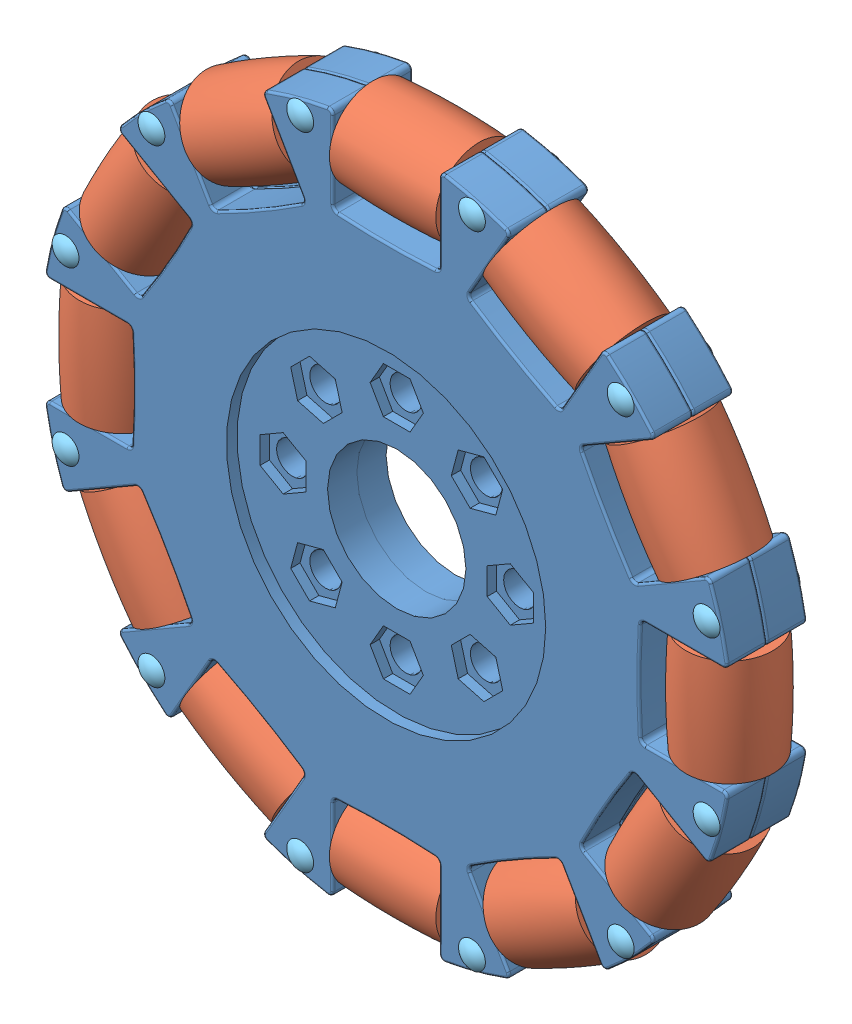
SolidWorks assembly omni assembly, configuration Default. Lengths in mm.
Overall size (136.3 136.3 22.3).
98 component instances, 5 part files, 11 mates.
Components (placement in the parent):
- omni 1-1: omni 1 [Default] at (56.9686 68.7963 88.8903) size (128.13 128.13 7.52)
- omni 1-2: omni 1 [Default] at (56.9686 68.7963 88.8903) x (-1 0 0) z (0 0 -1) size (128.13 128.13 7.52)
- roller assembly-1: roller assembly [Default] at (50.0152 30.7738 88.0959) x (1 0 0) z (0 -0.918252 -0.395997) size (24 16.97 16.97)
  - omni3-1: omni3 [Default] at (-3.0466 8.2445 17.1115) size (20 16.97 16.97)
  - omni4-1: omni4 [Default] at (-5.0466 8.2445 17.1115) x (0 0.996795 -0.079995) z (1 0 0) size (3 3 24)
  - instrument ball bearing_68_am-1: instrument ball bearing_68_am [AFBMA 12.1.4.1 - 0030-8 - 8,DE,NC,8_68] at (15.4534 8.2445 17.1115) size (3 8 8)
  - instrument ball bearing_68_am-2: instrument ball bearing_68_am [AFBMA 12.1.4.1 - 0030-8 - 8,DE,NC,8_68] at (-1.5466 8.2445 17.1115) size (3 8 8)
- truss head rivets gb-1: truss head rivets gb [GB_RIVETS_ROUND_TYPE87 2X11] at (101.0484 112.8761 80.3612) x (0 0 1) z (-1 0 0) size (12.03 5.04 5.04)
- truss head rivets gb-2: truss head rivets gb [GB_RIVETS_ROUND_TYPE87 2X11] at (101.0484 112.8761 93.4194) x (0 0 -1) z (1 0 0) size (12.03 5.04 5.04)
- truss head rivets gb-3: truss head rivets gb [GB_RIVETS_ROUND_TYPE87 2X11] at (101.0484 112.8761 97.4194) x (0 0 -1) z (1 0 0) size (12.03 5.04 5.04)
- roller assembly-2: roller assembly [Default] at (31.9355 39.3446 88.0959) x (0.866025 -0.5 0) z (-0.459126 -0.795229 -0.395997) size (24 16.97 16.97)
  - omni3-1: omni3 [Default] at (-3.0466 8.2445 17.1115) size (20 16.97 16.97)
  - omni4-1: omni4 [Default] at (-5.0466 8.2445 17.1115) x (0 0.996795 -0.079995) z (1 0 0) size (3 3 24)
  - instrument ball bearing_68_am-1: instrument ball bearing_68_am [AFBMA 12.1.4.1 - 0030-8 - 8,DE,NC,8_68] at (15.4534 8.2445 17.1115) size (3 8 8)
  - instrument ball bearing_68_am-2: instrument ball bearing_68_am [AFBMA 12.1.4.1 - 0030-8 - 8,DE,NC,8_68] at (-1.5466 8.2445 17.1115) size (3 8 8)
- roller assembly-3: roller assembly [Default] at (20.5635 55.8069 88.0959) x (0.5 -0.866025 0) z (-0.795229 -0.459126 -0.395997) size (24 16.97 16.97)
  - omni3-1: omni3 [Default] at (-3.0466 8.2445 17.1115) size (20 16.97 16.97)
  - omni4-1: omni4 [Default] at (-5.0466 8.2445 17.1115) x (0 0.996795 -0.079995) z (1 0 0) size (3 3 24)
  - instrument ball bearing_68_am-1: instrument ball bearing_68_am [AFBMA 12.1.4.1 - 0030-8 - 8,DE,NC,8_68] at (15.4534 8.2445 17.1115) size (3 8 8)
  - instrument ball bearing_68_am-2: instrument ball bearing_68_am [AFBMA 12.1.4.1 - 0030-8 - 8,DE,NC,8_68] at (-1.5466 8.2445 17.1115) size (3 8 8)
- roller assembly-4: roller assembly [Default] at (18.9461 75.7497 88.0959) x (0 -1 0) z (-0.918252 0 -0.395997) size (24 16.97 16.97)
  - omni3-1: omni3 [Default] at (-3.0466 8.2445 17.1115) size (20 16.97 16.97)
  - omni4-1: omni4 [Default] at (-5.0466 8.2445 17.1115) x (0 0.996795 -0.079995) z (1 0 0) size (3 3 24)
  - instrument ball bearing_68_am-1: instrument ball bearing_68_am [AFBMA 12.1.4.1 - 0030-8 - 8,DE,NC,8_68] at (15.4534 8.2445 17.1115) size (3 8 8)
  - instrument ball bearing_68_am-2: instrument ball bearing_68_am [AFBMA 12.1.4.1 - 0030-8 - 8,DE,NC,8_68] at (-1.5466 8.2445 17.1115) size (3 8 8)
- roller assembly-5: roller assembly [Default] at (27.5169 93.8294 88.0959) x (-0.5 -0.866025 0) z (-0.795229 0.459126 -0.395997) size (24 16.97 16.97)
  - omni3-1: omni3 [Default] at (-3.0466 8.2445 17.1115) size (20 16.97 16.97)
  - omni4-1: omni4 [Default] at (-5.0466 8.2445 17.1115) x (0 0.996795 -0.079995) z (1 0 0) size (3 3 24)
  - instrument ball bearing_68_am-1: instrument ball bearing_68_am [AFBMA 12.1.4.1 - 0030-8 - 8,DE,NC,8_68] at (15.4534 8.2445 17.1115) size (3 8 8)
  - instrument ball bearing_68_am-2: instrument ball bearing_68_am [AFBMA 12.1.4.1 - 0030-8 - 8,DE,NC,8_68] at (-1.5466 8.2445 17.1115) size (3 8 8)
- roller assembly-6: roller assembly [Default] at (43.9792 105.2015 88.0959) x (-0.866025 -0.5 0) z (-0.459126 0.795229 -0.395997) size (24 16.97 16.97)
  - omni3-1: omni3 [Default] at (-3.0466 8.2445 17.1115) size (20 16.97 16.97)
  - omni4-1: omni4 [Default] at (-5.0466 8.2445 17.1115) x (0 0.996795 -0.079995) z (1 0 0) size (3 3 24)
  - instrument ball bearing_68_am-1: instrument ball bearing_68_am [AFBMA 12.1.4.1 - 0030-8 - 8,DE,NC,8_68] at (15.4534 8.2445 17.1115) size (3 8 8)
  - instrument ball bearing_68_am-2: instrument ball bearing_68_am [AFBMA 12.1.4.1 - 0030-8 - 8,DE,NC,8_68] at (-1.5466 8.2445 17.1115) size (3 8 8)
- roller assembly-7: roller assembly [Default] at (63.922 106.8188 88.0959) x (-1 0 0) z (0 0.918252 -0.395997) size (24 16.97 16.97)
  - omni3-1: omni3 [Default] at (-3.0466 8.2445 17.1115) size (20 16.97 16.97)
  - omni4-1: omni4 [Default] at (-5.0466 8.2445 17.1115) x (0 0.996795 -0.079995) z (1 0 0) size (3 3 24)
  - instrument ball bearing_68_am-1: instrument ball bearing_68_am [AFBMA 12.1.4.1 - 0030-8 - 8,DE,NC,8_68] at (15.4534 8.2445 17.1115) size (3 8 8)
  - instrument ball bearing_68_am-2: instrument ball bearing_68_am [AFBMA 12.1.4.1 - 0030-8 - 8,DE,NC,8_68] at (-1.5466 8.2445 17.1115) size (3 8 8)
- roller assembly-8: roller assembly [Default] at (82.0017 98.2481 88.0959) x (-0.866025 0.5 0) z (0.459126 0.795229 -0.395997) size (24 16.97 16.97)
  - omni3-1: omni3 [Default] at (-3.0466 8.2445 17.1115) size (20 16.97 16.97)
  - omni4-1: omni4 [Default] at (-5.0466 8.2445 17.1115) x (0 0.996795 -0.079995) z (1 0 0) size (3 3 24)
  - instrument ball bearing_68_am-1: instrument ball bearing_68_am [AFBMA 12.1.4.1 - 0030-8 - 8,DE,NC,8_68] at (15.4534 8.2445 17.1115) size (3 8 8)
  - instrument ball bearing_68_am-2: instrument ball bearing_68_am [AFBMA 12.1.4.1 - 0030-8 - 8,DE,NC,8_68] at (-1.5466 8.2445 17.1115) size (3 8 8)
- roller assembly-9: roller assembly [Default] at (93.3738 81.7858 88.0959) x (-0.5 0.866025 0) z (0.795229 0.459126 -0.395997) size (24 16.97 16.97)
  - omni3-1: omni3 [Default] at (-3.0466 8.2445 17.1115) size (20 16.97 16.97)
  - omni4-1: omni4 [Default] at (-5.0466 8.2445 17.1115) x (0 0.996795 -0.079995) z (1 0 0) size (3 3 24)
  - instrument ball bearing_68_am-1: instrument ball bearing_68_am [AFBMA 12.1.4.1 - 0030-8 - 8,DE,NC,8_68] at (15.4534 8.2445 17.1115) size (3 8 8)
  - instrument ball bearing_68_am-2: instrument ball bearing_68_am [AFBMA 12.1.4.1 - 0030-8 - 8,DE,NC,8_68] at (-1.5466 8.2445 17.1115) size (3 8 8)
- roller assembly-10: roller assembly [Default] at (94.9911 61.8429 88.0959) x (0 1 0) z (0.918252 0 -0.395997) size (24 16.97 16.97)
  - omni3-1: omni3 [Default] at (-3.0466 8.2445 17.1115) size (20 16.97 16.97)
  - omni4-1: omni4 [Default] at (-5.0466 8.2445 17.1115) x (0 0.996795 -0.079995) z (1 0 0) size (3 3 24)
  - instrument ball bearing_68_am-1: instrument ball bearing_68_am [AFBMA 12.1.4.1 - 0030-8 - 8,DE,NC,8_68] at (15.4534 8.2445 17.1115) size (3 8 8)
  - instrument ball bearing_68_am-2: instrument ball bearing_68_am [AFBMA 12.1.4.1 - 0030-8 - 8,DE,NC,8_68] at (-1.5466 8.2445 17.1115) size (3 8 8)
- roller assembly-11: roller assembly [Default] at (86.4204 43.7633 88.0959) x (0.5 0.866025 0) z (0.795229 -0.459126 -0.395997) size (24 16.97 16.97)
  - omni3-1: omni3 [Default] at (-3.0466 8.2445 17.1115) size (20 16.97 16.97)
  - omni4-1: omni4 [Default] at (-5.0466 8.2445 17.1115) x (0 0.996795 -0.079995) z (1 0 0) size (3 3 24)
  - instrument ball bearing_68_am-1: instrument ball bearing_68_am [AFBMA 12.1.4.1 - 0030-8 - 8,DE,NC,8_68] at (15.4534 8.2445 17.1115) size (3 8 8)
  - instrument ball bearing_68_am-2: instrument ball bearing_68_am [AFBMA 12.1.4.1 - 0030-8 - 8,DE,NC,8_68] at (-1.5466 8.2445 17.1115) size (3 8 8)
- roller assembly-12: roller assembly [Default] at (69.9581 32.3912 88.0959) x (0.866025 0.5 0) z (0.459126 -0.795229 -0.395997) size (24 16.97 16.97)
  - omni3-1: omni3 [Default] at (-3.0466 8.2445 17.1115) size (20 16.97 16.97)
  - omni4-1: omni4 [Default] at (-5.0466 8.2445 17.1115) x (0 0.996795 -0.079995) z (1 0 0) size (3 3 24)
  - instrument ball bearing_68_am-1: instrument ball bearing_68_am [AFBMA 12.1.4.1 - 0030-8 - 8,DE,NC,8_68] at (15.4534 8.2445 17.1115) size (3 8 8)
  - instrument ball bearing_68_am-2: instrument ball bearing_68_am [AFBMA 12.1.4.1 - 0030-8 - 8,DE,NC,8_68] at (-1.5466 8.2445 17.1115) size (3 8 8)
- truss head rivets gb-4: truss head rivets gb [GB_RIVETS_ROUND_TYPE87 2X11] at (117.1827 84.9306 93.4194) x (0 0 -1) z (0.866025 -0.5 0) size (12.03 5.04 5.04)
- truss head rivets gb-5: truss head rivets gb [GB_RIVETS_ROUND_TYPE87 2X11] at (117.1827 52.662 93.4194) x (0 0 -1) z (0.5 -0.866025 0) size (12.03 5.04 5.04)
- truss head rivets gb-6: truss head rivets gb [GB_RIVETS_ROUND_TYPE87 2X11] at (101.0484 24.7166 93.4194) x (0 0 -1) z (0 -1 0) size (12.03 5.04 5.04)
- truss head rivets gb-7: truss head rivets gb [GB_RIVETS_ROUND_TYPE87 2X11] at (73.1029 8.5823 93.4194) x (0 0 -1) z (-0.5 -0.866025 0) size (12.03 5.04 5.04)
- truss head rivets gb-8: truss head rivets gb [GB_RIVETS_ROUND_TYPE87 2X11] at (40.8343 8.5823 93.4194) x (0 0 -1) z (-0.866025 -0.5 0) size (12.03 5.04 5.04)
- truss head rivets gb-9: truss head rivets gb [GB_RIVETS_ROUND_TYPE87 2X11] at (12.8889 24.7166 93.4194) x (0 0 -1) z (-1 0 0) size (12.03 5.04 5.04)
- truss head rivets gb-10: truss head rivets gb [GB_RIVETS_ROUND_TYPE87 2X11] at (-3.2455 52.662 93.4194) x (0 0 -1) z (-0.866025 0.5 0) size (12.03 5.04 5.04)
- truss head rivets gb-11: truss head rivets gb [GB_RIVETS_ROUND_TYPE87 2X11] at (-3.2455 84.9306 93.4194) x (0 0 -1) z (-0.5 0.866025 0) size (12.03 5.04 5.04)
- truss head rivets gb-12: truss head rivets gb [GB_RIVETS_ROUND_TYPE87 2X11] at (12.8889 112.8761 93.4194) x (0 0 -1) z (0 1 0) size (12.03 5.04 5.04)
- truss head rivets gb-13: truss head rivets gb [GB_RIVETS_ROUND_TYPE87 2X11] at (40.8343 129.0104 93.4194) x (0 0 -1) z (0.5 0.866025 0) size (12.03 5.04 5.04)
- truss head rivets gb-14: truss head rivets gb [GB_RIVETS_ROUND_TYPE87 2X11] at (73.1029 129.0104 93.4194) x (0 0 -1) z (0.866025 0.5 0) size (12.03 5.04 5.04)
- truss head rivets gb-15: truss head rivets gb [GB_RIVETS_ROUND_TYPE87 2X11] at (117.1827 84.9306 80.3612) x (0 0 1) z (-0.866025 0.5 0) size (12.03 5.04 5.04)
- truss head rivets gb-16: truss head rivets gb [GB_RIVETS_ROUND_TYPE87 2X11] at (117.1827 52.662 80.3612) x (0 0 1) z (-0.5 0.866025 0) size (12.03 5.04 5.04)
- truss head rivets gb-17: truss head rivets gb [GB_RIVETS_ROUND_TYPE87 2X11] at (101.0484 24.7166 80.3612) x (0 0 1) z (0 1 0) size (12.03 5.04 5.04)
- truss head rivets gb-18: truss head rivets gb [GB_RIVETS_ROUND_TYPE87 2X11] at (73.1029 8.5823 80.3612) x (0 0 1) z (0.5 0.866025 0) size (12.03 5.04 5.04)
- truss head rivets gb-19: truss head rivets gb [GB_RIVETS_ROUND_TYPE87 2X11] at (40.8343 8.5823 80.3612) x (0 0 1) z (0.866025 0.5 0) size (12.03 5.04 5.04)
- truss head rivets gb-20: truss head rivets gb [GB_RIVETS_ROUND_TYPE87 2X11] at (12.8889 24.7166 80.3612) x (0 0 1) z (1 0 0) size (12.03 5.04 5.04)
- truss head rivets gb-21: truss head rivets gb [GB_RIVETS_ROUND_TYPE87 2X11] at (-3.2455 52.662 80.3612) x (0 0 1) z (0.866025 -0.5 0) size (12.03 5.04 5.04)
- truss head rivets gb-22: truss head rivets gb [GB_RIVETS_ROUND_TYPE87 2X11] at (-3.2455 84.9306 80.3612) x (0 0 1) z (0.5 -0.866025 0) size (12.03 5.04 5.04)
- truss head rivets gb-23: truss head rivets gb [GB_RIVETS_ROUND_TYPE87 2X11] at (12.8889 112.8761 80.3612) x (0 0 1) z (0 -1 0) size (12.03 5.04 5.04)
- truss head rivets gb-24: truss head rivets gb [GB_RIVETS_ROUND_TYPE87 2X11] at (40.8343 129.0104 80.3612) x (0 0 1) z (-0.5 -0.866025 0) size (12.03 5.04 5.04)
- truss head rivets gb-25: truss head rivets gb [GB_RIVETS_ROUND_TYPE87 2X11] at (73.1029 129.0104 80.3612) x (0 0 1) z (-0.866025 -0.5 0) size (12.03 5.04 5.04)
- truss head rivets gb-26: truss head rivets gb [GB_RIVETS_ROUND_TYPE87 2X11] at (73.1029 129.0104 97.4194) x (0 0 -1) z (0.866025 0.5 0) size (12.03 5.04 5.04)
- truss head rivets gb-27: truss head rivets gb [GB_RIVETS_ROUND_TYPE87 2X11] at (40.8343 129.0104 97.4194) x (0 0 -1) z (0.5 0.866025 0) size (12.03 5.04 5.04)
- truss head rivets gb-28: truss head rivets gb [GB_RIVETS_ROUND_TYPE87 2X11] at (12.8889 112.8761 97.4194) x (0 0 -1) z (0 1 0) size (12.03 5.04 5.04)
- truss head rivets gb-29: truss head rivets gb [GB_RIVETS_ROUND_TYPE87 2X11] at (-3.2455 84.9306 97.4194) x (0 0 -1) z (-0.5 0.866025 0) size (12.03 5.04 5.04)
- truss head rivets gb-30: truss head rivets gb [GB_RIVETS_ROUND_TYPE87 2X11] at (-3.2455 52.662 97.4194) x (0 0 -1) z (-0.866025 0.5 0) size (12.03 5.04 5.04)
- truss head rivets gb-31: truss head rivets gb [GB_RIVETS_ROUND_TYPE87 2X11] at (12.8889 24.7166 97.4194) x (0 0 -1) z (-1 0 0) size (12.03 5.04 5.04)
- truss head rivets gb-32: truss head rivets gb [GB_RIVETS_ROUND_TYPE87 2X11] at (40.8343 8.5823 97.4194) x (0 0 -1) z (-0.866025 -0.5 0) size (12.03 5.04 5.04)
- truss head rivets gb-33: truss head rivets gb [GB_RIVETS_ROUND_TYPE87 2X11] at (73.1029 8.5823 97.4194) x (0 0 -1) z (-0.5 -0.866025 0) size (12.03 5.04 5.04)
- truss head rivets gb-34: truss head rivets gb [GB_RIVETS_ROUND_TYPE87 2X11] at (101.0484 24.7166 97.4194) x (0 0 -1) z (0 -1 0) size (12.03 5.04 5.04)
- truss head rivets gb-35: truss head rivets gb [GB_RIVETS_ROUND_TYPE87 2X11] at (117.1827 52.662 97.4194) x (0 0 -1) z (0.5 -0.866025 0) size (12.03 5.04 5.04)
- truss head rivets gb-36: truss head rivets gb [GB_RIVETS_ROUND_TYPE87 2X11] at (117.1827 84.9306 97.4194) x (0 0 -1) z (0.866025 -0.5 0) size (12.03 5.04 5.04)
Mates (geometry in assembly coordinates):
- Concentric1: concentric anti-aligned: cylinder of omni 1-1 through (56.9686 68.7963 96.3903) axis (0 0 -1) radius 65; cylinder of omni 1-2 through (56.9686 68.7963 81.3903) axis (0 0 1) radius 65
- Concentric2: concentric anti-aligned: cylinder of omni 1-1 through (56.9686 47.4646 88.8903) axis (0 0 1) radius 3; cylinder of omni 1-2 through (56.9686 47.4646 88.8903) axis (0 0 -1) radius 3
- Concentric3: concentric aligned: cylinder of omni 1-1 through (44.9686 11.7963 88.8903) axis (-1 0 0) radius 1.5; cylinder of roller assembly-1/omni4-1 through (68.9686 11.7963 88.8903) axis (-1 0 0) radius 1.5
- Coincident1: coincident anti-aligned: plane of omni 1-1 through (44.9686 11.7963 88.8903) normal (1 0 0); plane of roller assembly-1/omni4-1 through (44.9686 11.7963 88.8903) normal (-1 0 0)
- Coincident2: coincident anti-aligned: plane of omni 1-1 through (56.9686 68.7963 88.8903) normal (0 0 -1); plane of omni 1-2 through (56.9686 68.7963 88.8903) normal (0 0 1)
- Concentric5: concentric aligned: cylinder of omni 1-2 through (101.0484 112.8761 88.8903) axis (0 0 -1) radius 2; cylinder of truss head rivets gb-1 through (101.0484 112.8761 20.2668) axis (0 0 -1) radius 1
- Coincident3: coincident anti-aligned: plane of omni 1-2 through (56.9686 68.7963 81.3903) normal (0 0 -1); plane of truss head rivets gb-1 through (101.0484 113.9761 81.3903) normal (0 0 1)
- Concentric6: concentric anti-aligned: cylinder of truss head rivets gb-1 through (101.0484 112.8761 20.2668) axis (0 0 -1) radius 1; cylinder of truss head rivets gb-2 through (101.0484 112.8761 153.5138) axis (0 0 1) radius 1
- Coincident4: coincident anti-aligned: plane of truss head rivets gb-1 through (101.0484 112.8761 92.3903) normal (0 0 1); plane of truss head rivets gb-2 through (101.0484 113.9761 92.3903) normal (0 0 -1)
- Concentric7: concentric aligned: cylinder of omni 1-1 through (101.0484 112.8761 88.8903) axis (0 0 1) radius 2; cylinder of truss head rivets gb-3 through (101.0484 112.8761 157.5138) axis (0 0 1) radius 1
- Coincident5: coincident anti-aligned: plane of omni 1-1 through (56.9686 68.7963 96.3903) normal (0 0 1); plane of truss head rivets gb-3 through (101.0484 113.9761 96.3903) normal (0 0 -1)
